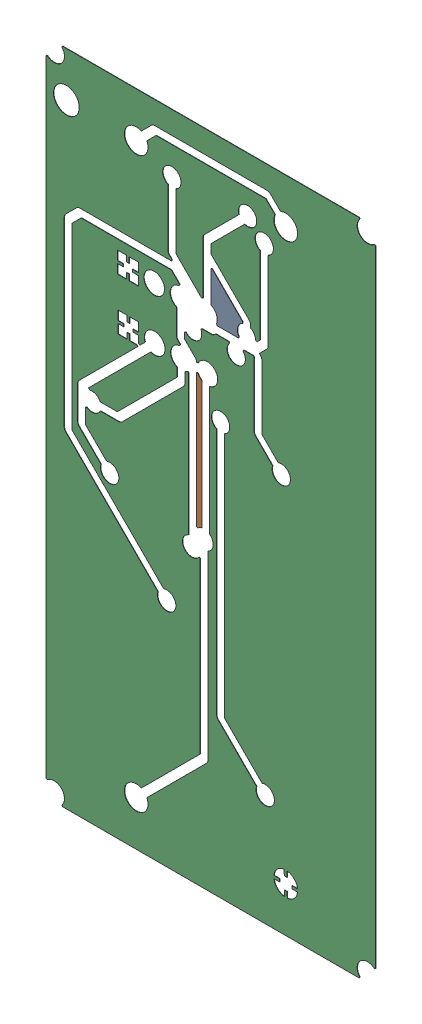
SolidWorks assembly Polygon  (GND_L02_P001) on Bottom Layer, configuration Predeterminado. Lengths in mm.
Overall size (31.76 63.51 0.04).
6 component instances, 3 part files, 0 mates.
Components (placement in the parent):
- Polygon Region (0 hole(s)) Bottom Layer-1: Polygon Region (0 hole(s)) Bottom Layer [Predeterminado] at (-68.317 -44.187 -0.4013) size (3.07 4.52 0.04)
  - Polygon Region (0 hole(s)) Bottom Layer-Part-1-1: Polygon Region (0 hole(s)) Bottom Layer-Part-1 [Predeterminado] at origin size (3.07 4.52 0.04)
- Polygon Region (0 hole(s)) Bottom Layer-1-1: Polygon Region (0 hole(s)) Bottom Layer-1 [Predeterminado] at (-68.317 -44.187 -0.4013) size (0.5 12.94 0.04)
  - Polygon Region (0 hole(s)) Bottom Layer-Part-1-1-1: Polygon Region (0 hole(s)) Bottom Layer-Part-1-1 [Predeterminado] at origin size (0.5 12.94 0.04)
- Polygon Region (16 hole(s)) Bottom Layer-1: Polygon Region (16 hole(s)) Bottom Layer [Predeterminado] at (-68.317 -44.187 -0.4013) size (31.76 63.51 0.04)
  - Polygon Region (16 hole(s)) Bottom Layer-Part-1-1: Polygon Region (16 hole(s)) Bottom Layer-Part-1 [Predeterminado] at origin size (31.76 63.51 0.04)
